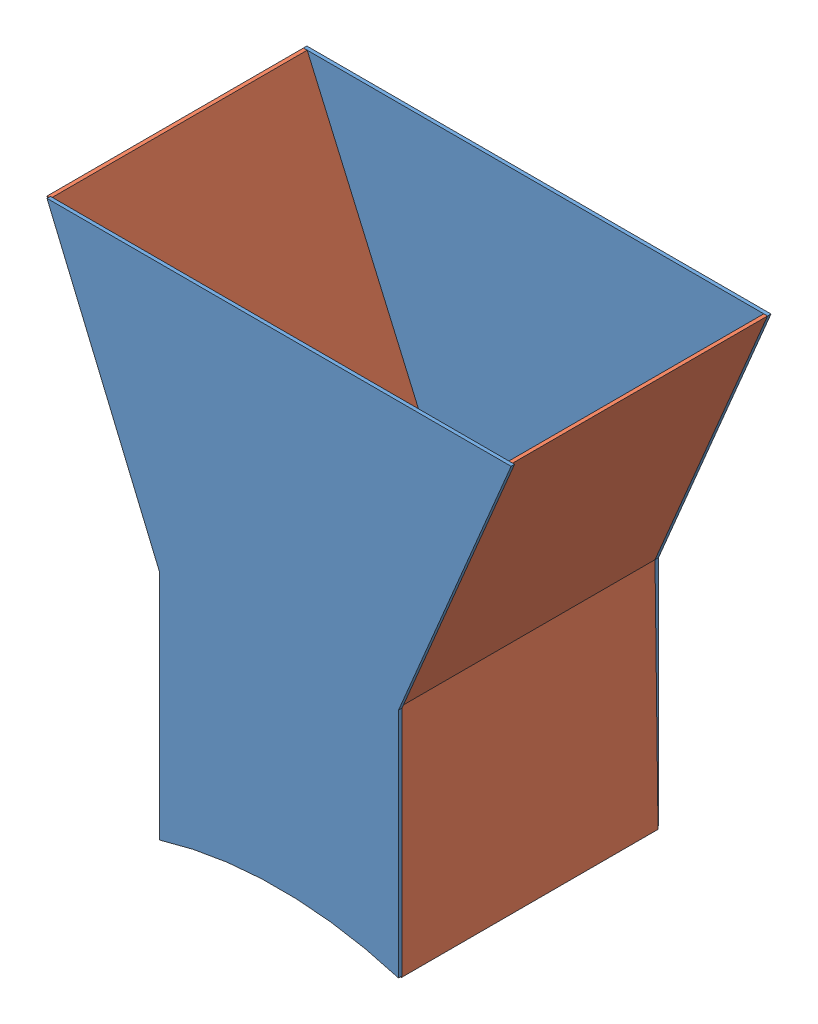
SolidWorks assembly Funnel Assembly 5.0, configuration Default. Lengths in mm.
Overall size (206.04 219.31 115.31).
4 component instances, 2 part files, 9 mates.
Components (placement in the parent):
- Funnel Assembly - Side Panel 5.0-1: Funnel Assembly - Side Panel 5.0 [Default] at (133.6737 -95.0914 315.1307) size (203.2 218.65 1.52)
- Funnel Assembly - Side Panel 5.0-2: Funnel Assembly - Side Panel 5.0 [Default] at (135.1963 -94.4386 428.9177) size (203.2 218.65 1.52)
- Funnel Assembly - Left and Right 5.0-1: Funnel Assembly - Left and Right 5.0 [Default] at (185.7991 76.4142 316.6497) x (0.999915 0.013044 0) z (0 0 1) size (52.32 218 112.27)
- Funnel Assembly - Left and Right 5.0-2: Funnel Assembly - Left and Right 5.0 [Default] at (84.3963 77.0782 428.9177) x (-1 0 0) z (0 0 -1) size (52.32 218 112.27)
Mates (geometry in assembly coordinates):
- Coincident4: coincident aligned: plane of Funnel Assembly - Side Panel 5.0-1 through (235.2737 295.074 316.6497) normal (0.921643 -0.38804 0); plane of Funnel Assembly - Left and Right 5.0-1 through (185.9926 178.0254 428.9177) normal (0.921643 -0.38804 0)
- Coincident5: coincident: line of Funnel Assembly - Side Panel 5.0-1 through (235.2737 295.074 316.6497) axis (-1 0 0); point of Funnel Assembly - Left and Right 5.0-1
- Coincident6: coincident anti-aligned: plane of Funnel Assembly - Side Panel 5.0-1 through (133.6737 -95.0914 316.6497) normal (0 0 1); plane of Funnel Assembly - Left and Right 5.0-1 through (185.7991 76.4142 316.6497) normal (0 0 -1)
- Coincident8: coincident anti-aligned: plane of Funnel Assembly - Side Panel 5.0-1 through (133.6737 -95.0914 316.6497) normal (0 0 1); plane of Funnel Assembly - Left and Right 5.0-2 through (84.3963 77.0782 316.6497) normal (0 0 -1)
- Coincident9: coincident: line of Funnel Assembly - Side Panel 5.0-1 through (32.0737 295.074 316.6497) axis (0 0 -1); point of Funnel Assembly - Left and Right 5.0-2
- Parallel2: parallel aligned: plane of Funnel Assembly - Side Panel 5.0-1 through (81.3547 76.4254 316.6497) normal (-1 0 0); plane of Funnel Assembly - Left and Right 5.0-2 through (82.8774 77.0782 316.6497) normal (-1 0 0)
- Coincident11: coincident anti-aligned: plane of Funnel Assembly - Side Panel 5.0-2 through (135.1963 -94.4386 428.9177) normal (0 0 -1); plane of Funnel Assembly - Left and Right 5.0-1 through (185.7991 76.4142 428.9177) normal (0 0 1)
- Coincident17: coincident anti-aligned: line of Funnel Assembly - Side Panel 5.0-2 through (82.8774 178.6782 428.9177) axis (0 -1 0); line of Funnel Assembly - Left and Right 5.0-2 through (82.8774 77.0782 428.9177) axis (0 1 0)
- Coincident18: coincident anti-aligned: line of Funnel Assembly - Side Panel 5.0-2 through (82.8774 178.6782 430.4366) axis (0 0 -1); line of Funnel Assembly - Left and Right 5.0-2 through (82.8774 178.6782 316.6497) axis (0 0 1)
